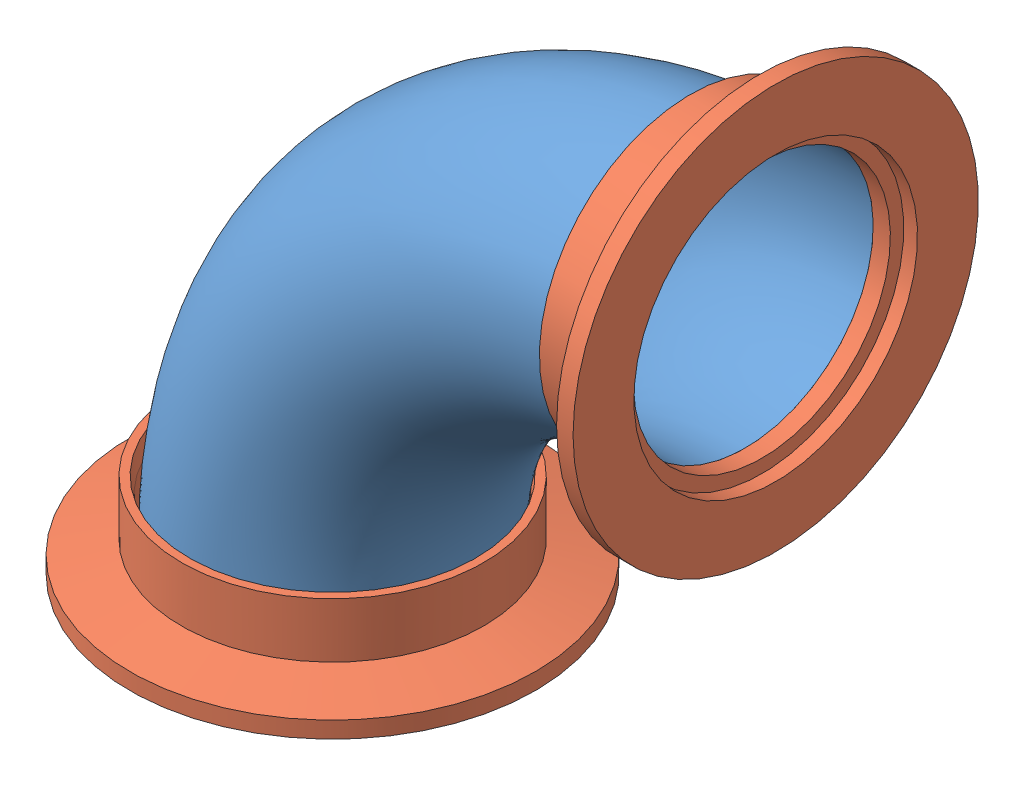
SolidWorks assembly 723003, configuration Default. Lengths in mm.
Overall size (127.69 134.89 105.96).
3 component instances, 2 part files, 5 mates.
Components (placement in the parent):
- 403503-1: 403503 [Default] at (21.87 12.7165 65.9243) size (101.6 101.6 50.8)
- 972303-1: 972303 [Default] at (21.87 7.0015 65.9243) x (0.966996 0 0.25479) z (0.25479 0 -0.966996) size (74.93 15.75 74.93)
- 972303-2: 972303 [Default] at (103.785 88.9165 65.9243) x (0 0.71673 0.697351) z (0 0.697351 -0.71673) size (74.93 15.75 74.93)
Mates (geometry in assembly coordinates):
- Concentric1: concentric aligned: circle of 403503-1; circle of 972303-1
- Coincident2: coincident anti-aligned: plane of 403503-1 through (21.87 12.7165 65.9243) normal (0 -1 0); plane of 972303-1 through (46.9844 12.7165 72.5416) normal (0 1 0)
- Concentric2: concentric aligned: circle of 403503-1; circle of 972303-2
- Coincident3: coincident anti-aligned: plane of 403503-1 through (98.07 88.9165 65.9243) normal (1 0 0); plane of 972303-2 through (98.07 107.5311 84.0356) normal (-1 0 0)
- Concentric3: concentric anti-aligned: circle of 403503-1; circle of 972303-1
